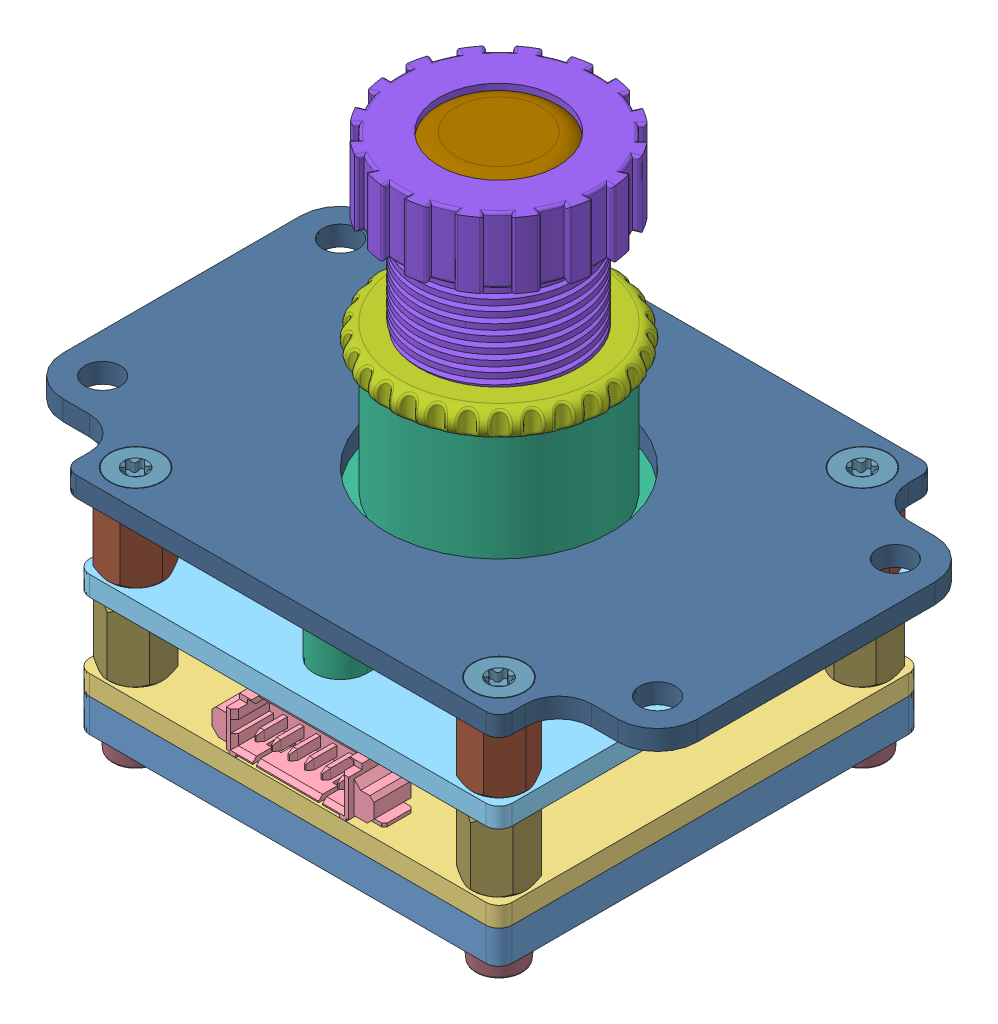
SolidWorks assembly piCAM_Integration_Model, configuration Default. Lengths in mm.
Overall size (48 40.55 33).
31 component instances, 14 part files, 0 mates.
Components (placement in the parent):
- piCAM_Integration_Model.stp-1: piCAM_Integration_Model.stp [Default] at origin size (48 40.55 33)
  - piCAM_bot.stp-1: piCAM_bot.stp [Default] at (19.1667 -39.5908 231.4278) size (32 2.68 32)
    - piCAM_bot_1.stp-1: piCAM_bot_1.stp [Default] at (-3.1667 6.0093 16) size (32 2.5 32)
    - logo.stp-1: logo.stp [Default] at (10.127 6.0093 29.3051) x (0 -1 0) z (0 0 -1) size (0.19 16.12 8.3)
  - piCAM_pcb.stp-1: piCAM_pcb.stp [Default] at (16.7593 -33.1496 231.5047) x (1 0 0) z (0 0 -1) size (32 4.9 32)
    - piCAM_pcb_1.stp-1: piCAM_pcb_1.stp [Default] at (-0.7593 -3.568 16.0769) size (32 1.5 32)
    - 532610671 Tin.stp-1: 532610671 Tin.stp [Default] at (-16.7593 -5.368 -14.9481) x (-1 0 0) z (0 -1 0) size (12.65 5.2 3.4)
  - cam_module.stp-1: cam_module.stp [Default] at (0 -27.4427 231.0575) x (0 0 -1) z (-1 0 0) size (32 17.5 32)
    - piCAM_1.stp-1: piCAM_1.stp [Default] at (15.6296 -4.3611 16) size (32 1.5 32)
    - camere_alodine.stp-1: camere_alodine.stp [Default] at (-0.3704 -4.3611 0) x (1 0 0) z (0 -1 0) size (28 22 14)
    - cam_nut.stp-1: cam_nut.stp [Default] at (-0.3704 -18.3611 0) x (1 0 0) z (0 -1 0) size (17.03 17.05 2)
  - Camera end.stp-1: Camera end.stp [Default] at (3.5334 -3.1753 232.8058) x (0.467281 0 0.884109) z (0 1 0) size (16 16 17)
    - Camera end_1.stp-1: Camera end_1.stp [Default] at (-2.8704 -2.5 -8.4062) size (16 16 17)
    - Len.stp-1: Len.stp [Default] at (-2.8704 -2.5 8.0938) size (9 9 0.5)
  - piCAM_top.stp-1: piCAM_top.stp [Default] at (-24 -16.5816 214.9278) x (0 0 -1) z (-1 0 0) size (33 1.5 48)
  - M2x5mm_FF.stp-1: M2x5mm_FF.stp [Default] at (13.75 -20.5816 217.6778) x (0.994227 0 0.107295) z (0 1 0) size (4.62 4 5)
  - M2x5mm.stp-1: M2x5mm.stp [Default] at (13.75 -24.5816 217.6778) x (0.066233 0 0.997804) z (0 1 0) size (4.62 4 10)
  - M2x5mm_FF.stp-2: M2x5mm_FF.stp [Default] at (13.75 -20.5816 245.1778) x (0.994227 0 0.107295) z (0 1 0) size (4.62 4 5)
  - M2x5mm.stp-2: M2x5mm.stp [Default] at (13.75 -24.5816 245.1778) x (0.066233 0 0.997804) z (0 1 0) size (4.62 4 10)
  - M2x5mm_FF.stp-3: M2x5mm_FF.stp [Default] at (-13.75 -20.5816 217.6778) x (0.994227 0 0.107295) z (0 1 0) size (4.62 4 5)
  - M2x5mm.stp-3: M2x5mm.stp [Default] at (-13.75 -24.5816 217.6778) x (0.066233 0 0.997804) z (0 1 0) size (4.62 4 10)
  - M2x5mm_FF.stp-4: M2x5mm_FF.stp [Default] at (-13.75 -20.5816 245.1778) x (0.994227 0 0.107295) z (0 1 0) size (4.62 4 5)
  - M2x5mm.stp-4: M2x5mm.stp [Default] at (-13.75 -24.5816 245.1778) x (0.066233 0 0.997804) z (0 1 0) size (4.62 4 10)
  - BN 15857 3108689 hexalobular socket head cap screw M2x3.stp-1: BN 15857 3108689 hexalobular socket head cap screw M2x3.stp [Default] at (-13.75 -33.5816 217.6778) x (0 1 0) z (0.999308 0 -0.037206) size (4.55 3.8 3.8)
  - BN 15857 3108689 hexalobular socket head cap screw M2x3.stp-2: BN 15857 3108689 hexalobular socket head cap screw M2x3.stp [Default] at (13.75 -33.5816 217.6778) x (0 1 0) z (0.999308 0 -0.037206) size (4.55 3.8 3.8)
  - BN 15857 3108689 hexalobular socket head cap screw M2x3.stp-3: BN 15857 3108689 hexalobular socket head cap screw M2x3.stp [Default] at (-13.75 -33.5816 245.1778) x (0 1 0) z (0.999308 0 -0.037206) size (4.55 3.8 3.8)
  - BN 15857 3108689 hexalobular socket head cap screw M2x3.stp-4: BN 15857 3108689 hexalobular socket head cap screw M2x3.stp [Default] at (13.75 -33.5816 245.1778) x (0 1 0) z (0.999308 0 -0.037206) size (4.55 3.8 3.8)
  - BN 4851 3271457 hexalobular socket countersunk flat head screw M2x5.stp-1: BN 4851 3271457 hexalobular socket countersunk flat head screw M2x5.stp [Default] at (-13.75 -16.5816 245.1778) x (0 -1 0) z (0.181685 0 -0.983357) size (5 3.8 3.8)
  - BN 4851 3271457 hexalobular socket countersunk flat head screw M2x5.stp-2: BN 4851 3271457 hexalobular socket countersunk flat head screw M2x5.stp [Default] at (-13.75 -16.5816 217.6778) x (0 -1 0) z (0.181685 0 -0.983357) size (5 3.8 3.8)
  - BN 4851 3271457 hexalobular socket countersunk flat head screw M2x5.stp-3: BN 4851 3271457 hexalobular socket countersunk flat head screw M2x5.stp [Default] at (13.75 -16.5816 245.1778) x (0 -1 0) z (0.181685 0 -0.983357) size (5 3.8 3.8)
  - BN 4851 3271457 hexalobular socket countersunk flat head screw M2x5.stp-4: BN 4851 3271457 hexalobular socket countersunk flat head screw M2x5.stp [Default] at (13.75 -16.5816 217.6778) x (0 -1 0) z (0.181685 0 -0.983357) size (5 3.8 3.8)
